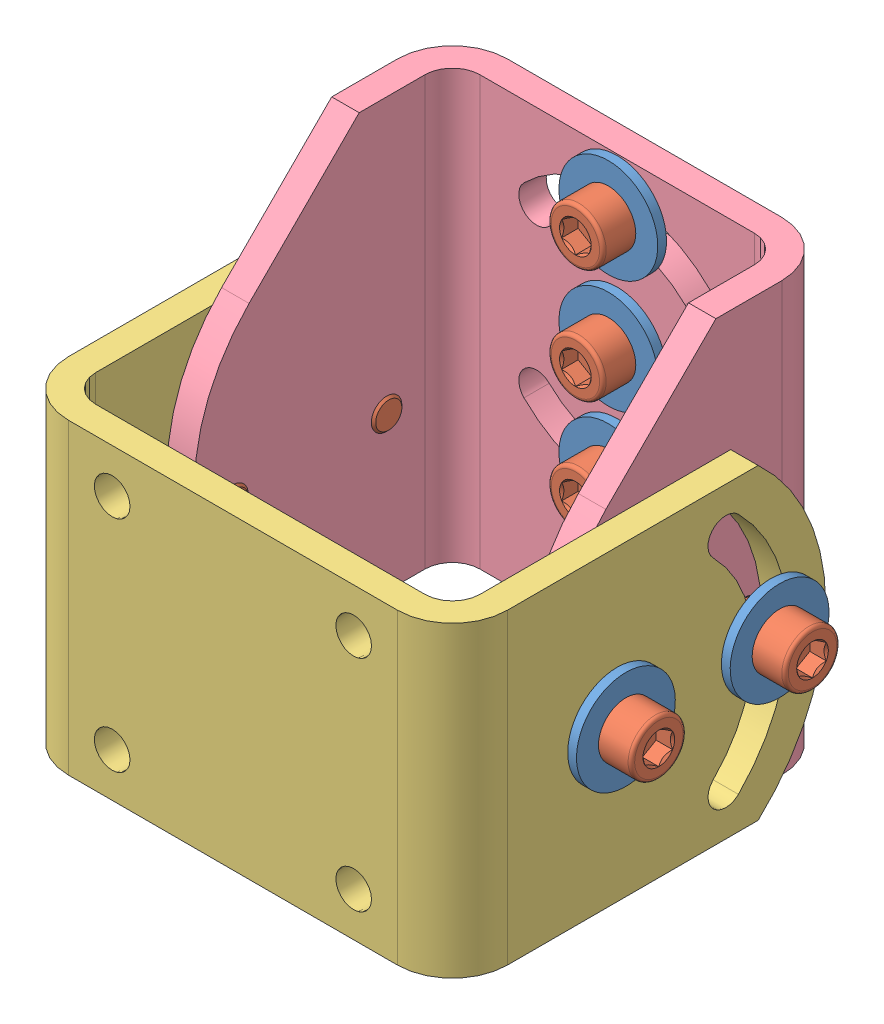
SolidWorks assembly 2046025-S029876, configuration Default. Lengths in mm.
Overall size (95.76 78 80.4).
16 component instances, 4 part files, 0 mates.
Components (placement in the parent):
- 5310226_Scheibe_6.4_DIN9021_A2.2_1-1: 5310226_Scheibe_6.4_DIN9021_A2.2_1 [Default] at (0 15.8126 61.1) x (1 0 0) z (0 -1 0) size (18 1.6 18)
- 5321646_DIN_EN_ISO4762_M6x12.2-1: 5321646_DIN_EN_ISO4762_M6x12.2 [Default] at (166.5438 358.5597 -321.0466) x (0 0 -1) z (-1 0 0) size (10 10 18.28)
- 5321646_DIN_EN_ISO4762_M6x12.2-2: 5321646_DIN_EN_ISO4762_M6x12.2 [Default] at (-166.5438 358.5597 556.0466) x (0 0 1) z (1 0 0) size (10 10 18.28)
- 5321646_DIN_EN_ISO4762_M6x12.2-3: 5321646_DIN_EN_ISO4762_M6x12.2 [Default] at (-166.5438 358.5597 528.0466) x (0 0 1) z (1 0 0) size (10 10 18.28)
- 5321646_DIN_EN_ISO4762_M6x12.2-4: 5321646_DIN_EN_ISO4762_M6x12.2 [Default] at (424.5466 357.8097 218.0438) x (1 0 0) z (0 0 -1) size (10 10 18.28)
- 5321646_DIN_EN_ISO4762_M6x12.2-5: 5321646_DIN_EN_ISO4762_M6x12.2 [Default] at (424.5466 378.5597 218.0438) x (1 0 0) z (0 0 -1) size (10 10 18.28)
- 5321646_DIN_EN_ISO4762_M6x12.2-6: 5321646_DIN_EN_ISO4762_M6x12.2 [Default] at (166.5438 358.5597 -293.0466) x (0 0 -1) z (-1 0 0) size (10 10 18.28)
- 5310226_Scheibe_6.4_DIN9021_A2.2_1-2: 5310226_Scheibe_6.4_DIN9021_A2.2_1 [Default] at (-9.6 -24.9374 103.5) x (0 0 1) z (0 -1 0) size (18 1.6 18)
- 5310226_Scheibe_6.4_DIN9021_A2.2_1-3: 5310226_Scheibe_6.4_DIN9021_A2.2_1 [Default] at (9.6 -24.9374 103.5) x (0 0 -1) z (0 -1 0) size (18 1.6 18)
- 4054296_Winkelflansch_Anlage_1-1: 4054296_Winkelflansch_Anlage_1 [Default] at (0 -33 25) size (80 56 68)
- 5310226_Scheibe_6.4_DIN9021_A2.2_1-4: 5310226_Scheibe_6.4_DIN9021_A2.2_1 [Default] at (9.6 -24.9374 131.5) x (0 0 -1) z (0 -1 0) size (18 1.6 18)
- 5321646_DIN_EN_ISO4762_M6x12.2-7: 5321646_DIN_EN_ISO4762_M6x12.2 [Default] at (424.5466 399.3097 218.0438) x (1 0 0) z (0 0 -1) size (10 10 18.28)
- 5310226_Scheibe_6.4_DIN9021_A2.2_1-5: 5310226_Scheibe_6.4_DIN9021_A2.2_1 [Default] at (-9.6 -24.9374 131.5) x (0 0 1) z (0 -1 0) size (18 1.6 18)
- 5310226_Scheibe_6.4_DIN9021_A2.2_1-6: 5310226_Scheibe_6.4_DIN9021_A2.2_1 [Default] at (0 -4.9374 61.1) x (1 0 0) z (0 -1 0) size (18 1.6 18)
- 5310226_Scheibe_6.4_DIN9021_A2.2_1-7: 5310226_Scheibe_6.4_DIN9021_A2.2_1 [Default] at (0 -25.6874 61.1) x (1 0 0) z (0 -1 0) size (18 1.6 18)
- 4054298_Winkelflansch_Wetterschutzhaube_1-1: 4054298_Winkelflansch_Wetterschutzhaube_1 [Default] at (0 -13 20) size (70 78 52)
